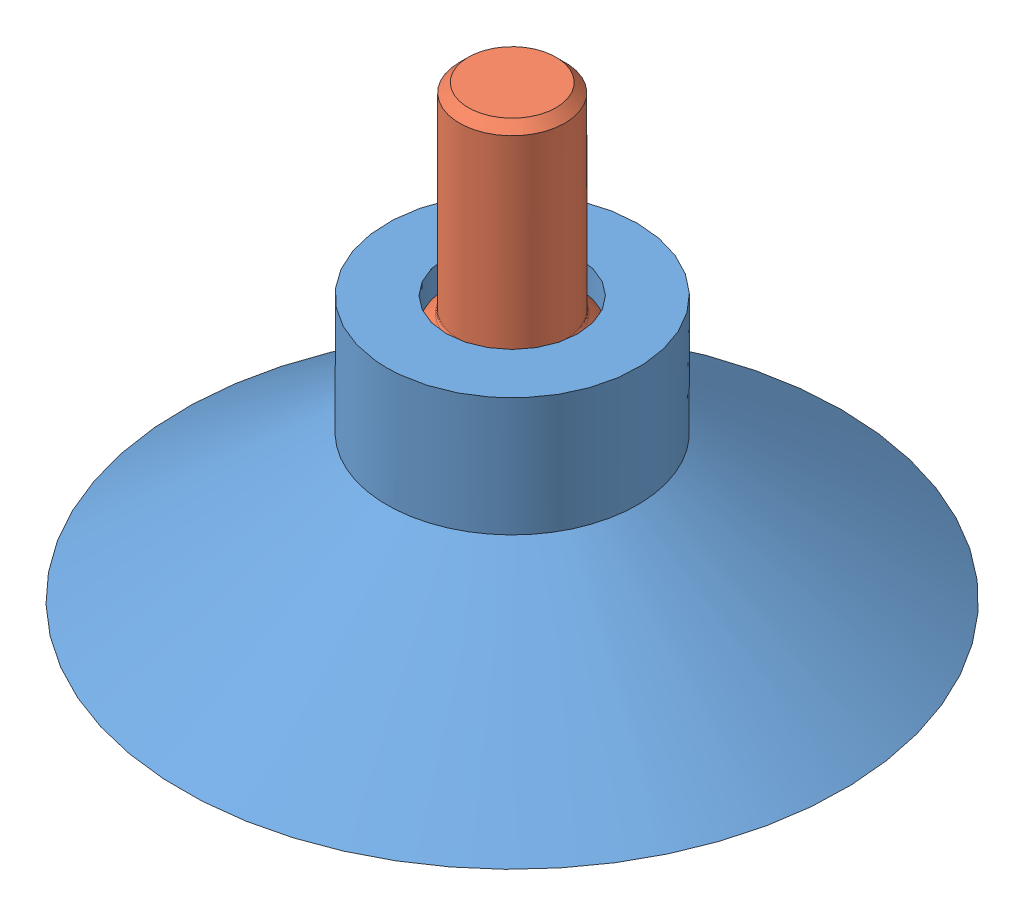
SolidWorks assembly 底座吸盘, configuration 默认. Lengths in mm.
Overall size (50 34 50).
2 component instances, 2 part files, 2 mates.
Components (placement in the parent):
- 底座吸盘-1: 底座吸盘 [默认] at origin size (50 20 50)
- hexagon socket countersunk head screws gb-2: hexagon socket countersunk head screws gb [GB_FASTENER_SCREWS_HSCHS M8X20-N] at (0 3 0) x (0 1 0) z (-0.546944 0 0.837169) size (20 15.24 15.24)
Mates (geometry in assembly coordinates):
- 重合1: coincident anti-aligned: plane of 底座吸盘-1 through (0 3 0) normal (0 1 0); plane of hexagon socket countersunk head screws gb-2 through (0 3 0) normal (0 -1 0)
- 同心1: concentric anti-aligned: circle of 底座吸盘-1; circle of hexagon socket countersunk head screws gb-2
